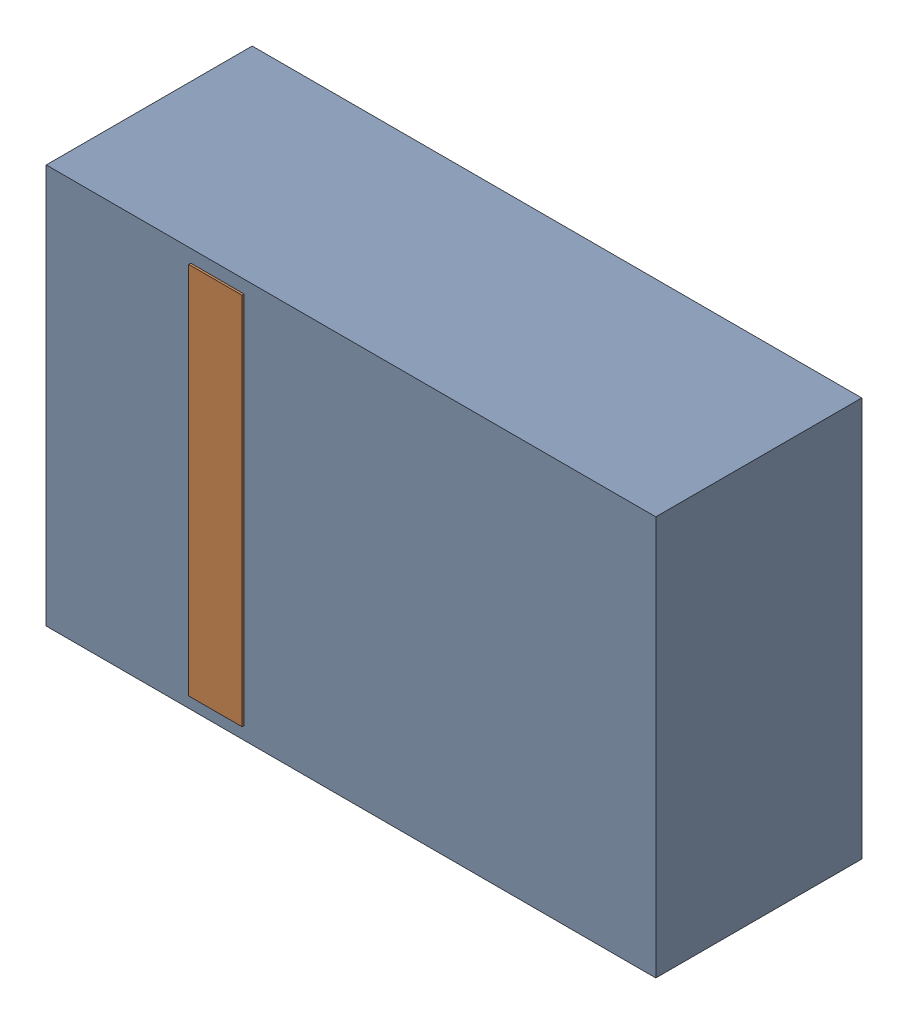
SolidWorks assembly D2, configuration Default. Lengths in mm.
Overall size (2.9 1.9 0.99).
4 component instances, 2 part files, 0 mates.
Components (placement in the parent):
- 905269392-1: 905269392 [Default] at (4.4767 73.803 0) size (2.9 1.9 0.98)
  - Extruded_5-1: Extruded_5 [Default] at origin size (2.9 1.9 0.98)
- 905269800-1: 905269800 [Default] at (3.8418 73.803 0.95) size (0.25 1.78 0.04)
  - Extruded_6-1: Extruded_6 [Default] at origin size (0.25 1.78 0.04)
